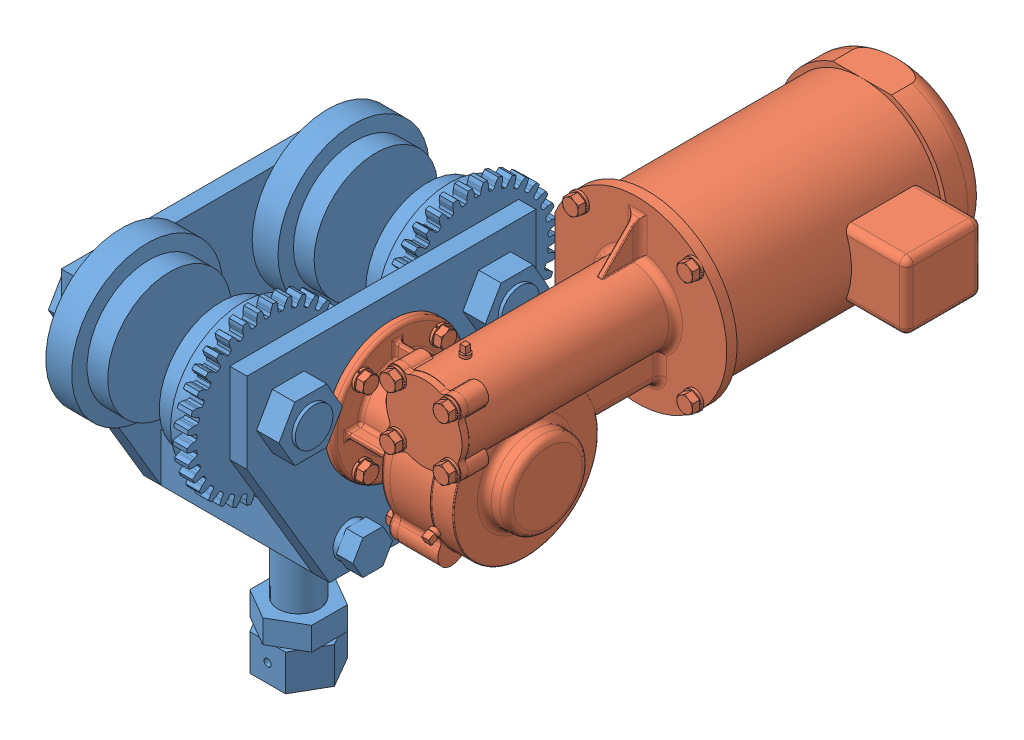
SolidWorks assembly M2631C-RH, configuration Default. Lengths in mm.
Overall size (422.97 413.65 540.72).
2 component instances, 2 part files, 3 mates.
Components (placement in the parent):
- Copy of M2631C-TROLLEY-SECTION^M2631C-RH-1: Copy of M2631C-TROLLEY-SECTION^M2631C-RH [3.25 PAT TRACK] at origin size (219.2 375.83 342.81) (virtual)
- Copy of SDT GEAR REDUCER TEMPLATE^M2631C-RH-1: Copy of SDT GEAR REDUCER TEMPLATE^M2631C-RH [Default] at (188.9125 120.2538 0) size (229.23 225.42 451.54) (virtual)
Mates (geometry in assembly coordinates):
- Coincident1: coincident aligned: plane of Copy of M2631C-TROLLEY-SECTION^M2631C-RH-1 through (0 0 0) normal (0 0 1); plane of Copy of SDT GEAR REDUCER TEMPLATE^M2631C-RH-1 through (188.9125 120.2538 0) normal (0 0 1)
- Coincident2: coincident aligned: plane of Copy of M2631C-TROLLEY-SECTION^M2631C-RH-1 through (0 120.2538 0) normal (0 1 0); plane of Copy of SDT GEAR REDUCER TEMPLATE^M2631C-RH-1 through (188.9125 120.2538 0) normal (0 1 0)
- Distance1: distance = 14.2875 mm aligned: plane of Copy of SDT GEAR REDUCER TEMPLATE^M2631C-RH-1 through (84.1375 120.2538 0) normal (-1 0 0); plane of Copy of M2631C-TROLLEY-SECTION^M2631C-RH-1 through (69.85 0 -133.35) normal (-1 0 0)
